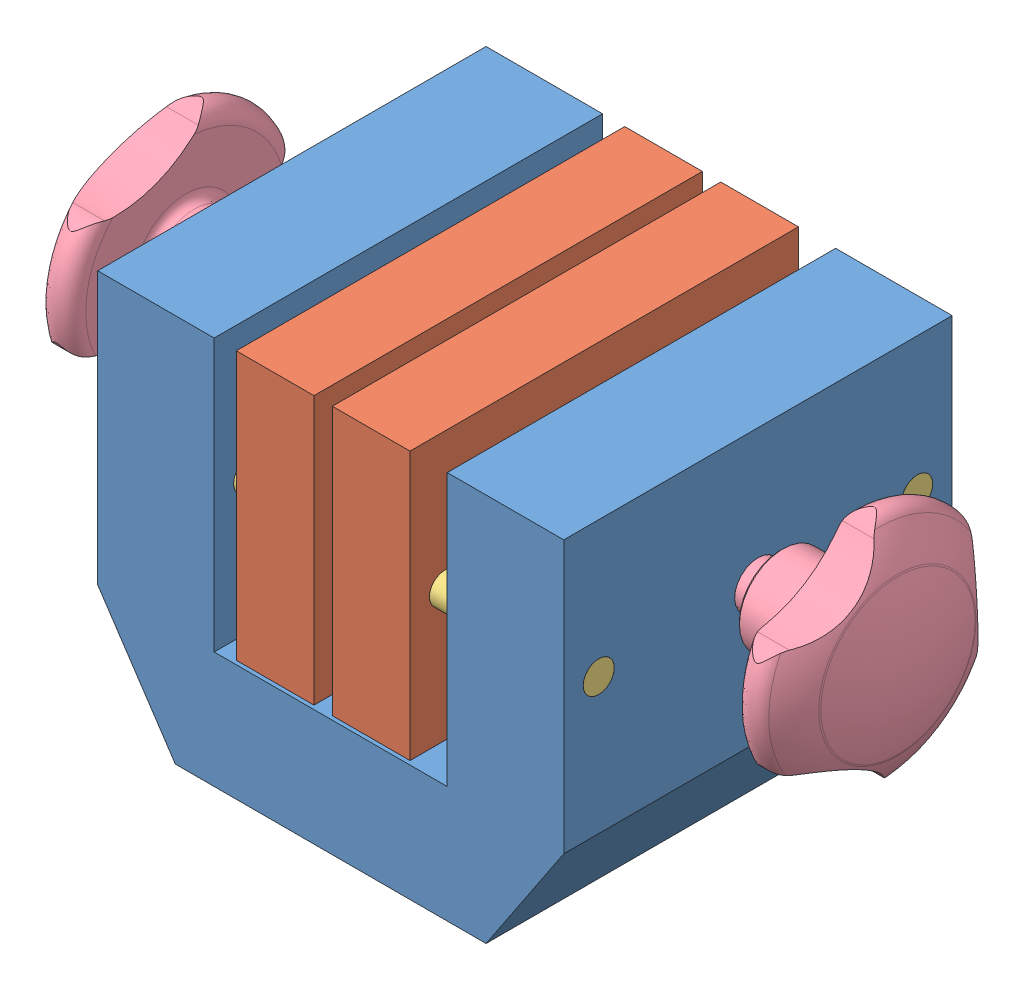
SolidWorks assembly mount_loadCell, configuration Domyślna. Lengths in mm.
Overall size (202.72 100 100).
7 component instances, 4 part files, 27 mates.
Components (placement in the parent):
- body_loadCell-1: body_loadCell [Domyślna] at (-6.687 13.6734 100) size (120 100 100)
- clamp-1: clamp [Domyślna] at (-10.9898 28.6734 150) x (0 0 1) z (-1 0 0) size (100 69 20)
- clamp-2: clamp [Domyślna] at (-6.2685 28.6734 150) x (0 0 -1) z (1 0 0) size (100 69 20)
- shaft_specimen_mount-1: shaft_specimen_mount [Domyślna] at (-66.687 28.6734 109) size (120 8 8)
- shaft_specimen_mount-2: shaft_specimen_mount [Domyślna] at (-66.687 28.6734 191) size (120 8 8)
- Three-lobe handwheel VTT.60-p-M12x60.stp-3: Three-lobe handwheel VTT.60-p-M12x60.stp [Domyślna] at (-1.2685 28.6734 150) x (1 0 0) z (0 -0.999018 -0.044301) size (94 57.21 59.57)
- Three-lobe handwheel VTT.60-p-M12x60.stp-4: Three-lobe handwheel VTT.60-p-M12x60.stp [Domyślna] at (-15.9898 28.6734 150) x (-1 0 0) z (0 0.987885 -0.15519) size (94 57.21 59.57)
Mates (geometry in assembly coordinates):
- Concentric1: concentric anti-aligned: cylinder of body_loadCell-1 through (-66.687 28.6734 109) axis (1 0 0) radius 4; cylinder of shaft-2 through (53.313 28.6734 109) axis (-1 0 0) radius 4
- Coincident1: coincident aligned: plane of body_loadCell-1 through (53.313 -36.3266 200) normal (1 0 0); plane of shaft-2 through (53.313 28.6734 109) normal (1 0 0)
- Concentric2: concentric anti-aligned: cylinder of body_loadCell-1 through (-66.687 28.6734 191) axis (1 0 0) radius 4; cylinder of shaft-1 through (53.313 28.6734 191) axis (-1 0 0) radius 4
- Coincident2: coincident aligned: plane of body_loadCell-1 through (-66.687 -36.3266 200) normal (-1 0 0); plane of shaft-1 through (-66.687 28.6734 191) normal (-1 0 0)
- Concentric3: concentric anti-aligned: cylinder of shaft-1 through (53.313 28.6734 191) axis (-1 0 0) radius 4; cylinder of clamp-1 through (-32.6539 28.6734 191) axis (1 0 0) radius 4.1
- Concentric4: concentric anti-aligned: cylinder of shaft-2 through (53.313 28.6734 109) axis (-1 0 0) radius 4; cylinder of clamp-1 through (-32.6539 28.6734 109) axis (1 0 0) radius 4.1
- Concentric5: concentric aligned: cylinder of shaft-1 through (53.313 28.6734 191) axis (-1 0 0) radius 4; cylinder of clamp-2 through (20.8314 28.6734 191) axis (-1 0 0) radius 4.1
- Concentric6: concentric aligned: cylinder of shaft-2 through (53.313 28.6734 109) axis (-1 0 0) radius 4; cylinder of clamp-2 through (20.8314 28.6734 109) axis (-1 0 0) radius 4.1
- Coincident3: coincident aligned: plane of shaft_specimen_mount-1 through (-66.687 28.6734 109) normal (-1 0 0); plane of shaft_specimen_mount-2 through (-66.687 28.6734 191) normal (-1 0 0)
- Coincident4: coincident aligned: plane of body_loadCell-1 through (-66.687 -36.3266 200) normal (-1 0 0); plane of shaft_specimen_mount-1 through (-66.687 28.6734 109) normal (-1 0 0)
- Concentric7: concentric anti-aligned: cylinder of body_loadCell-1 through (-66.687 28.6734 109) axis (1 0 0) radius 4; cylinder of shaft_specimen_mount-1 through (53.313 28.6734 109) axis (-1 0 0) radius 4
- Concentric8: concentric anti-aligned: cylinder of body_loadCell-1 through (-66.687 28.6734 191) axis (1 0 0) radius 4; cylinder of shaft_specimen_mount-2 through (53.313 28.6734 191) axis (-1 0 0) radius 4
- Concentric9: concentric anti-aligned: circle of body_loadCell-1; cylinder of Adjustable clamping lever with bolt GN 99.2-10-M8-63-M.stp-1 through (7.1866 28.6734 150) axis (-1 0 0) radius 4
- Coincident5: coincident anti-aligned: plane of clamp-2 through (-1.2685 28.6734 150) normal (1 0 0); plane of Adjustable clamping lever with bolt GN 99.2-10-M8-63-M.stp-1 through (7.1866 28.8721 153.2269) normal (-1 0 0)
- Concentric10: concentric anti-aligned: circle of clamp-2; cylinder of Adjustable clamping lever with bolt GN 99.2-10-M8-63-M.stp-1 through (7.1866 28.6734 150) axis (-1 0 0) radius 4
- Concentric11: concentric aligned: cylinder of clamp-2 through (13.7315 28.6734 109) axis (-1 0 0) radius 4; cylinder of shaft_specimen_mount-1 through (53.313 28.6734 109) axis (-1 0 0) radius 4
- Concentric12: concentric aligned: cylinder of clamp-2 through (13.7315 28.6734 191) axis (-1 0 0) radius 4; cylinder of shaft_specimen_mount-2 through (53.313 28.6734 191) axis (-1 0 0) radius 4
- Concentric13: concentric anti-aligned: cylinder of clamp-1 through (-30.9898 28.6734 109) axis (1 0 0) radius 4; cylinder of shaft_specimen_mount-1 through (53.313 28.6734 109) axis (-1 0 0) radius 4
- Concentric14: concentric anti-aligned: cylinder of clamp-1 through (-30.9898 28.6734 191) axis (1 0 0) radius 4; cylinder of shaft_specimen_mount-2 through (53.313 28.6734 191) axis (-1 0 0) radius 4
- Concentric15: concentric aligned: cylinder of body_loadCell-1 through (-66.687 28.6734 150) axis (1 0 0) radius 6; cylinder of Three-lobe handwheel VTT.60-p-M12x60.stp-1 through (61.5127 28.6734 150) axis (1 0 0) radius 6
- Concentric16: concentric anti-aligned: cylinder of body_loadCell-1 through (-66.687 28.6734 150) axis (1 0 0) radius 6; cylinder of Three-lobe handwheel VTT.60-p-M12x60.stp-2 through (-75.9898 28.6734 150) axis (-1 0 0) radius 6
- Coincident6: coincident anti-aligned: plane of clamp-1 through (-15.9898 28.6734 150) normal (-1 0 0); plane of Three-lobe handwheel VTT.60-p-M12x60.stp-2 through (-15.9898 28.6734 150) normal (1 0 0)
- Coincident7: coincident anti-aligned: plane of clamp-2 through (-1.2685 28.6734 150) normal (1 0 0); plane of Three-lobe handwheel VTT.60-p-M12x60.stp-1 through (1.5127 28.6734 150) normal (-1 0 0)
- Concentric17: concentric aligned: cylinder of body_loadCell-1 through (-66.687 28.6734 150) axis (1 0 0) radius 6; cylinder of Three-lobe handwheel VTT.60-p-M12x60.stp-3 through (58.7315 28.6734 150) axis (1 0 0) radius 6
- Coincident8: coincident anti-aligned: plane of clamp-2 through (-1.2685 28.6734 150) normal (1 0 0); plane of Three-lobe handwheel VTT.60-p-M12x60.stp-3 through (-1.2685 28.6734 150) normal (-1 0 0)
- Concentric18: concentric anti-aligned: cylinder of body_loadCell-1 through (-66.687 28.6734 150) axis (1 0 0) radius 6; cylinder of Three-lobe handwheel VTT.60-p-M12x60.stp-4 through (-75.9898 28.6734 150) axis (-1 0 0) radius 6
- Coincident9: coincident aligned: plane of clamp-1 through (-15.9898 28.6734 150) normal (-1 0 0); circle of Three-lobe handwheel VTT.60-p-M12x60.stp-4
